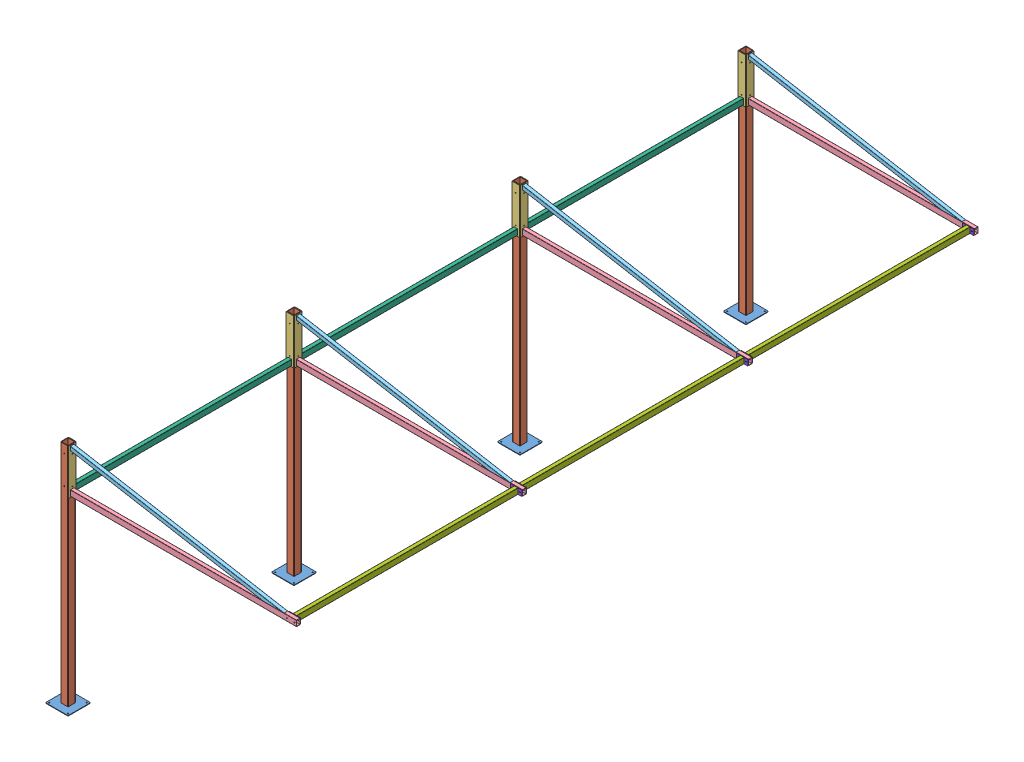
SolidWorks assembly welding area, configuration Default. Lengths in mm.
Overall size (3257.55 3054.35 9448.8).
57 component instances, 9 part files, 47 mates.
Components (placement in the parent):
- upright assy-1: upright assy [Default] at origin size (304.8 3054.35 304.8)
  - base plate-1: base plate [Default] at origin size (304.8 6.35 304.8)
  - upright-1: upright [Default] at (0 1530.35 0) size (101.6 3048 101.6)
- upright assy-2: upright assy [Default] at (0 0 3048) size (304.8 3054.35 304.8)
  - base plate-1: base plate [Default] at origin size (304.8 6.35 304.8)
  - upright-1: upright [Default] at (0 1530.35 0) size (101.6 3048 101.6)
- upright assy-3: upright assy [Default] at (0 0 -3048) size (304.8 3054.35 304.8)
  - base plate-1: base plate [Default] at origin size (304.8 6.35 304.8)
  - upright-1: upright [Default] at (0 1530.35 0) size (101.6 3048 101.6)
- upright assy-4: upright assy [Default] at (0 0 -6096) size (304.8 3054.35 304.8)
  - base plate-1: base plate [Default] at origin size (304.8 6.35 304.8)
  - upright-1: upright [Default] at (0 1530.35 0) size (101.6 3048 101.6)
- curtain arm assy-1: curtain arm assy [Default] at (50.8 2749.55 -3048) x (0 0 -1) z (1 0 0) size (101.6 609.6 3056.82)
  - tube mount-1: tube mount [Default] at origin size (101.6 609.6 6.35)
  - curtain arm main-1: curtain arm main [Default] at (0 -254 1530.35) size (50.8 76.2 3048)
  - gusset tube-1: gusset tube [Default] at (0 2.4461 1502.7864) x (1 0 0) z (0 -0.173648 0.984808) size (50.8 50.8 2925.46)
- curtain arm assy-2: curtain arm assy [Default] at (50.8 2749.55 0) x (0 0 -1) z (1 0 0) size (101.6 609.6 3056.82)
  - tube mount-1: tube mount [Default] at origin size (101.6 609.6 6.35)
  - curtain arm main-1: curtain arm main [Default] at (0 -254 1530.35) size (50.8 76.2 3048)
  - gusset tube-1: gusset tube [Default] at (0 2.4461 1502.7864) x (1 0 0) z (0 -0.173648 0.984808) size (50.8 50.8 2925.46)
- curtain arm assy-3: curtain arm assy [Default] at (50.8 2749.55 3048) x (0 0 -1) z (1 0 0) size (101.6 609.6 3056.82)
  - tube mount-1: tube mount [Default] at origin size (101.6 609.6 6.35)
  - curtain arm main-1: curtain arm main [Default] at (0 -254 1530.35) size (50.8 76.2 3048)
  - gusset tube-1: gusset tube [Default] at (0 2.4461 1502.7864) x (1 0 0) z (0 -0.173648 0.984808) size (50.8 50.8 2925.46)
- curtain arm assy-4: curtain arm assy [Default] at (50.8 2749.55 -6096) x (0 0 -1) z (1 0 0) size (101.6 609.6 3056.82)
  - tube mount-1: tube mount [Default] at origin size (101.6 609.6 6.35)
  - curtain arm main-1: curtain arm main [Default] at (0 -254 1530.35) size (50.8 76.2 3048)
  - gusset tube-1: gusset tube [Default] at (0 2.4461 1502.7864) x (1 0 0) z (0 -0.173648 0.984808) size (50.8 50.8 2925.46)
- cross bar assy-1: cross bar assy [Default] at (0 2495.55 1524) size (101.6 609.6 2946.4)
  - cross bar-1: cross bar [Default] at origin size (50.8 76.2 2933.7)
  - tube mount-1: tube mount [Default] at (0 254 1466.85) size (101.6 609.6 6.35)
  - tube mount-2: tube mount [Default] at (0 254 -1473.2) size (101.6 609.6 6.35)
- cross bar assy-3: cross bar assy [Default] at (0 2495.55 -1524) size (101.6 609.6 2946.4)
  - cross bar-1: cross bar [Default] at origin size (50.8 76.2 2933.7)
  - tube mount-1: tube mount [Default] at (0 254 1466.85) size (101.6 609.6 6.35)
  - tube mount-2: tube mount [Default] at (0 254 -1473.2) size (101.6 609.6 6.35)
- cross bar assy-4: cross bar assy [Default] at (0 2495.55 -4572) size (101.6 609.6 2946.4)
  - cross bar-1: cross bar [Default] at origin size (50.8 76.2 2933.7)
  - tube mount-1: tube mount [Default] at (0 254 1466.85) size (101.6 609.6 6.35)
  - tube mount-2: tube mount [Default] at (0 254 -1473.2) size (101.6 609.6 6.35)
- curtain-1: curtain [Default] at (1581.15 349.25 0) x (0 0 -1) z (1 0 0) size (3.17 2362.2 3048) (hidden)
- curtain-2: curtain [Default] at (1581.15 349.25 3048) x (0 0 1) z (-1 0 0) size (3.17 2362.2 3048) (hidden)
- curtain-3: curtain [Default] at (1581.15 349.25 -3048) x (0 0 1) z (-1 0 0) size (3.17 2362.2 3048) (hidden)
- curtain-4: curtain [Default] at (1581.15 349.25 -6096) x (0 0 1) z (-1 0 0) size (3.17 2362.2 3048) (hidden)
- front cross bar-1: front cross bar [Default] at (3028.95 2495.55 -4572) size (152.4 76.2 2997.2)
  - outer cross bar-1: outer cross bar [Default] at origin size (50.8 76.2 2984.5)
  - front cross mount-1: front cross mount [Default] at (0 0 1492.25) x (0 1 0) z (0 0 1) size (76.2 152.4 6.35)
  - front cross mount-2: front cross mount [Default] at (0 0 -1498.6) x (0 -1 0) z (0 0 1) size (76.2 152.4 6.35)
- curtain-5: curtain [Default] at (3028.95 349.25 -4562.4829) x (-1 0 0) z (0 0 -1) size (3.17 2362.2 3048) (hidden)
- front cross bar-2: front cross bar [Default] at (3028.95 2495.55 -1524) size (152.4 76.2 2997.2)
  - outer cross bar-1: outer cross bar [Default] at origin size (50.8 76.2 2984.5)
  - front cross mount-1: front cross mount [Default] at (0 0 1492.25) x (0 1 0) z (0 0 1) size (76.2 152.4 6.35)
  - front cross mount-2: front cross mount [Default] at (0 0 -1498.6) x (0 -1 0) z (0 0 1) size (76.2 152.4 6.35)
- front cross bar-3: front cross bar [Default] at (3028.95 2495.55 1524) size (152.4 76.2 2997.2)
  - outer cross bar-1: outer cross bar [Default] at origin size (50.8 76.2 2984.5)
  - front cross mount-1: front cross mount [Default] at (0 0 1492.25) x (0 1 0) z (0 0 1) size (76.2 152.4 6.35)
  - front cross mount-2: front cross mount [Default] at (0 0 -1498.6) x (0 -1 0) z (0 0 1) size (76.2 152.4 6.35)
Mates (geometry in assembly coordinates):
- Coincident1: coincident aligned: plane of upright assy-2/base plate-1 through (0 0 3048) normal (1 0 0); plane of assembly through (0 0 0) normal (1 0 0)
- Coincident2: coincident aligned: plane of upright assy-3/base plate-1 through (0 0 -3048) normal (1 0 0); plane of assembly through (0 0 0) normal (1 0 0)
- Coincident3: coincident aligned: plane of upright assy-4/base plate-1 through (0 0 -6096) normal (1 0 0); plane of assembly through (0 0 0) normal (1 0 0)
- Distance1: distance = 3048 mm aligned: plane of assembly through (0 0 0) normal (0 0 1); plane of upright assy-2/base plate-1 through (0 0 3048) normal (0 0 1)
- Distance2: distance = 3048 mm aligned: plane of assembly through (0 0 0) normal (0 0 1); plane of upright assy-3/base plate-1 through (0 0 -3048) normal (0 0 1)
- Distance3: distance = 6096 mm aligned: plane of assembly through (0 0 0) normal (0 0 1); plane of upright assy-4/base plate-1 through (0 0 -6096) normal (0 0 1)
- Coincident7: coincident aligned: plane of upright assy-3/base plate-1 through (-139.7 0 -2908.3) normal (0 -1 0); plane of upright assy-4/base plate-1 through (-139.7 0 -5956.3) normal (0 -1 0)
- Coincident8: coincident aligned: plane of upright assy-1/base plate-1 through (-139.7 0 139.7) normal (0 -1 0); plane of upright assy-3/base plate-1 through (-139.7 0 -2908.3) normal (0 -1 0)
- Coincident9: coincident aligned: plane of upright assy-2/base plate-1 through (-139.7 0 3187.7) normal (0 -1 0); plane of upright assy-3/base plate-1 through (-139.7 0 -2908.3) normal (0 -1 0)
- Coincident10: coincident anti-aligned: plane of upright assy-3/upright-1 through (50.8 3054.35 -3092.45) normal (1 0 0); plane of curtain arm assy-1/tube mount-1 through (50.8 3048 -3003.55) normal (-1 0 0)
- Concentric1: concentric aligned: cylinder of upright assy-3/upright-1 through (-50.8 2940.05 -3048) axis (1 0 0) radius 6.5024; cylinder of curtain arm assy-1/tube mount-1 through (50.8 2940.05 -3048) axis (1 0 0) radius 6.5024
- Concentric2: concentric aligned: cylinder of upright assy-3/upright-1 through (-50.8 2559.05 -3048) axis (1 0 0) radius 6.5024; cylinder of curtain arm assy-1/tube mount-1 through (50.8 2559.05 -3048) axis (1 0 0) radius 6.5024
- Coincident11: coincident anti-aligned: plane of upright assy-1/upright-1 through (50.8 3054.35 -44.45) normal (1 0 0); plane of curtain arm assy-2/tube mount-1 through (50.8 3048 44.45) normal (-1 0 0)
- Concentric3: concentric aligned: cylinder of upright assy-1/upright-1 through (-50.8 2940.05 0) axis (1 0 0) radius 6.5024; cylinder of curtain arm assy-2/tube mount-1 through (50.8 2940.05 0) axis (1 0 0) radius 6.5024
- Concentric4: concentric aligned: cylinder of upright assy-1/upright-1 through (-50.8 2559.05 0) axis (1 0 0) radius 6.5024; cylinder of curtain arm assy-2/tube mount-1 through (50.8 2559.05 0) axis (1 0 0) radius 6.5024
- Coincident12: coincident anti-aligned: plane of upright assy-2/upright-1 through (50.8 3054.35 3003.55) normal (1 0 0); plane of curtain arm assy-3/tube mount-1 through (50.8 3048 3092.45) normal (-1 0 0)
- Concentric6: concentric aligned: cylinder of upright assy-2/upright-1 through (-50.8 2940.05 3048) axis (1 0 0) radius 6.5024; cylinder of curtain arm assy-3/tube mount-1 through (50.8 2940.05 3048) axis (1 0 0) radius 6.5024
- Concentric7: concentric aligned: cylinder of upright assy-2/upright-1 through (-50.8 2559.05 3048) axis (1 0 0) radius 6.5024; cylinder of curtain arm assy-3/tube mount-1 through (50.8 2559.05 3048) axis (1 0 0) radius 6.5024
- Coincident13: coincident anti-aligned: plane of upright assy-4/upright-1 through (50.8 3054.35 -6140.45) normal (1 0 0); plane of curtain arm assy-4/tube mount-1 through (50.8 3048 -6051.55) normal (-1 0 0)
- Concentric8: concentric aligned: cylinder of upright assy-4/upright-1 through (-50.8 2940.05 -6096) axis (1 0 0) radius 6.5024; cylinder of curtain arm assy-4/tube mount-1 through (50.8 2940.05 -6096) axis (1 0 0) radius 6.5024
- Concentric9: concentric aligned: cylinder of upright assy-4/upright-1 through (-50.8 2559.05 -6096) axis (1 0 0) radius 6.5024; cylinder of curtain arm assy-4/tube mount-1 through (50.8 2559.05 -6096) axis (1 0 0) radius 6.5024
- Concentric10: concentric anti-aligned: cylinder of upright assy-2/upright-1 through (0 2559.05 3098.8) axis (0 0 -1) radius 6.5024; cylinder of cross bar assy-1/tube mount-1 through (0 2559.05 2990.85) axis (0 0 1) radius 6.5024
- Concentric11: concentric anti-aligned: cylinder of upright assy-2/upright-1 through (0 2940.05 3098.8) axis (0 0 -1) radius 6.5024; cylinder of cross bar assy-1/tube mount-1 through (0 2940.05 2990.85) axis (0 0 1) radius 6.5024
- Coincident14: coincident anti-aligned: plane of upright assy-2/upright-1 through (-44.45 3054.35 2997.2) normal (0 0 -1); plane of cross bar assy-1/tube mount-1 through (-44.45 3048 2997.2) normal (0 0 1)
- Concentric14: concentric anti-aligned: cylinder of upright assy-1/upright-1 through (0 2559.05 50.8) axis (0 0 -1) radius 6.5024; cylinder of cross bar assy-3/tube mount-1 through (0 2559.05 -57.15) axis (0 0 1) radius 6.5024
- Concentric15: concentric anti-aligned: cylinder of upright assy-1/upright-1 through (0 2940.05 50.8) axis (0 0 -1) radius 6.5024; cylinder of cross bar assy-3/tube mount-1 through (0 2940.05 -57.15) axis (0 0 1) radius 6.5024
- Coincident16: coincident anti-aligned: plane of upright assy-1/upright-1 through (-44.45 3054.35 -50.8) normal (0 0 -1); plane of cross bar assy-3/tube mount-1 through (-44.45 3048 -50.8) normal (0 0 1)
- Concentric16: concentric anti-aligned: cylinder of upright assy-3/upright-1 through (0 2559.05 -2997.2) axis (0 0 -1) radius 6.5024; cylinder of cross bar assy-4/tube mount-1 through (0 2559.05 -3105.15) axis (0 0 1) radius 6.5024
- Concentric17: concentric anti-aligned: cylinder of upright assy-3/upright-1 through (0 2940.05 -2997.2) axis (0 0 -1) radius 6.5024; cylinder of cross bar assy-4/tube mount-1 through (0 2940.05 -3105.15) axis (0 0 1) radius 6.5024
- Coincident17: coincident anti-aligned: plane of upright assy-3/upright-1 through (-44.45 3054.35 -3098.8) normal (0 0 -1); plane of cross bar assy-4/tube mount-1 through (-44.45 3048 -3098.8) normal (0 0 1)
- Coincident18: coincident anti-aligned: plane of curtain-1 through (1581.15 349.25 0) normal (0 0 -1); plane of assembly through (0 0 0) normal (0 0 1)
- Coincident19: coincident aligned: plane of curtain arm assy-2/curtain arm main-1 through (1581.15 2495.55 0) normal (1 0 0); plane of curtain-1 through (1581.15 349.25 0) normal (1 0 0)
- Distance4: distance = 50.8 mm anti-aligned: plane of curtain arm assy-2/curtain arm main-1 through (3105.15 2457.45 22.225) normal (0 -1 0); plane of curtain-1 through (3105.15 2406.65 -1.5875) normal (0 1 0)
- Coincident21: coincident anti-aligned: plane of curtain arm assy-3/tube mount-1 through (50.8 2749.55 3048) normal (0 0 -1); plane of curtain-2 through (1581.15 349.25 3048) normal (0 0 1)
- Coincident22: coincident anti-aligned: plane of curtain arm assy-3/curtain arm main-1 through (1581.15 2495.55 3048) normal (1 0 0); plane of curtain-2 through (1581.15 349.25 3048) normal (-1 0 0)
- Distance5: distance = 50.8 mm anti-aligned: plane of curtain arm assy-3/curtain arm main-1 through (3105.15 2457.45 3070.225) normal (0 -1 0); plane of curtain-2 through (57.15 2406.65 3049.5875) normal (0 1 0)
- Coincident23: coincident anti-aligned: plane of curtain arm assy-1/tube mount-1 through (50.8 2749.55 -3048) normal (0 0 -1); plane of curtain-3 through (1581.15 349.25 -3048) normal (0 0 1)
- Coincident24: coincident anti-aligned: plane of curtain arm assy-1/curtain arm main-1 through (1581.15 2495.55 -3048) normal (1 0 0); plane of curtain-3 through (1581.15 349.25 -3048) normal (-1 0 0)
- Distance6: distance = 50.8 mm anti-aligned: plane of curtain arm assy-1/curtain arm main-1 through (3105.15 2457.45 -3025.775) normal (0 -1 0); plane of curtain-3 through (57.15 2406.65 -3046.4125) normal (0 1 0)
- Coincident25: coincident anti-aligned: plane of curtain arm assy-4/tube mount-1 through (50.8 2749.55 -6096) normal (0 0 -1); plane of curtain-4 through (1581.15 349.25 -6096) normal (0 0 1)
- Coincident26: coincident anti-aligned: plane of curtain arm assy-4/curtain arm main-1 through (1581.15 2495.55 -6096) normal (1 0 0); plane of curtain-4 through (1581.15 349.25 -6096) normal (-1 0 0)
- Distance7: distance = 50.8 mm anti-aligned: plane of curtain arm assy-4/curtain arm main-1 through (3105.15 2457.45 -6073.775) normal (0 -1 0); plane of curtain-4 through (57.15 2406.65 -6094.4125) normal (0 1 0)
- Coincident27: coincident aligned: plane of cross bar assy-4/cross bar-1 through (0 2495.55 -4572) normal (0 0 1); plane of front cross bar-1/outer cross bar-1 through (3028.95 2495.55 -4572) normal (0 0 1)
- Coincident28: coincident aligned: plane of curtain arm assy-4/curtain arm main-1 through (3105.15 2533.65 -6073.775) normal (0 1 0); plane of front cross bar-1/outer cross bar-1 through (3006.725 2533.65 -3079.75) normal (0 1 0)
- Coincident29: coincident aligned: plane of curtain arm assy-4/curtain arm main-1 through (3105.15 2460.625 -6073.775) normal (1 0 0); plane of front cross bar-1/front cross mount-2 through (3105.15 2527.3 -6064.25) normal (1 0 0)
- Coincident30: coincident anti-aligned: plane of front cross bar-1/outer cross bar-1 through (3028.95 2495.55 -4572) normal (1 0 0); plane of curtain-5 through (3028.95 349.25 -4562.4829) normal (-1 0 0)
- Distance8: distance = 50.8 mm anti-aligned: plane of curtain-5 through (3027.3625 2406.65 -6086.4829) normal (0 1 0); plane of front cross bar-1/outer cross bar-1 through (3006.725 2457.45 -3079.75) normal (0 -1 0)
